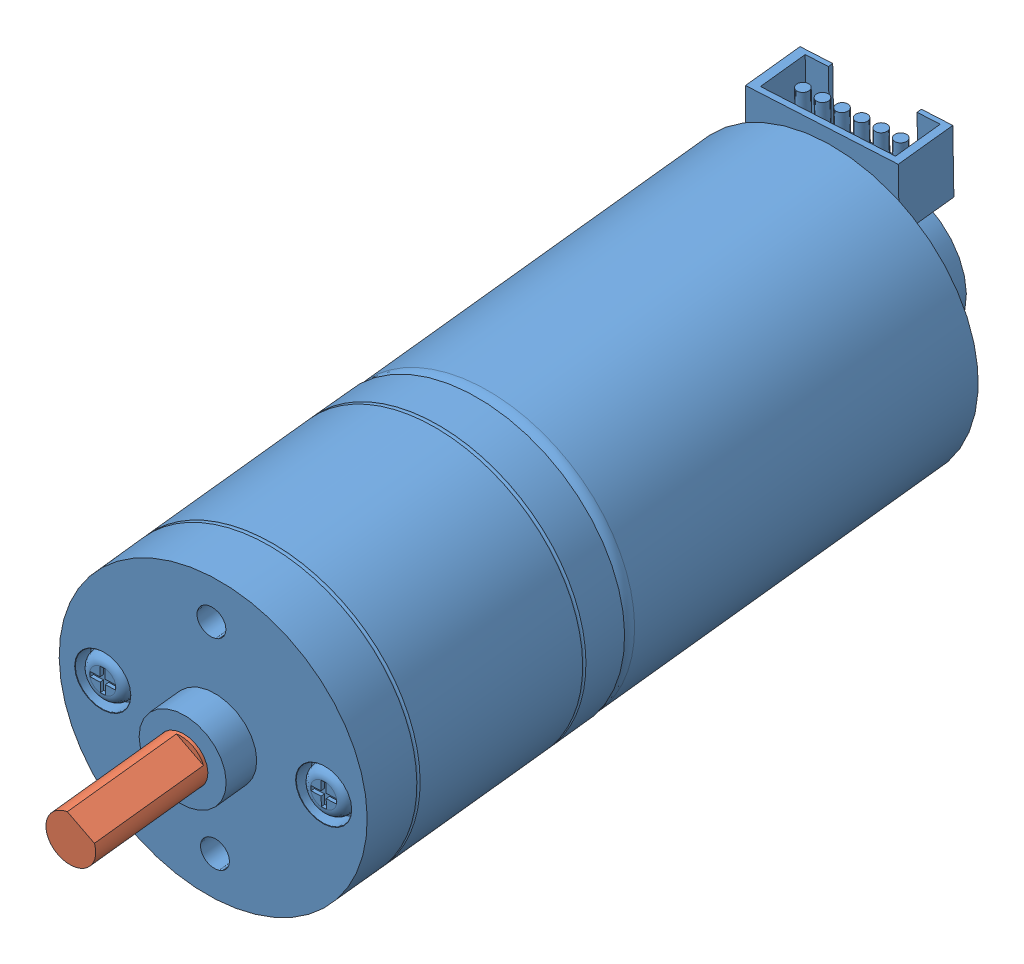
SolidWorks assembly 6V Motor Spin, configuration Default. Lengths in mm.
Overall size (29.63 28.32 78.39).
2 component instances, 2 part files, 2 mates.
Components (placement in the parent):
- Motor no spinny boi-1: Motor no spinny boi [Default] at (39.6165 36.3483 7.7453) x (0.997226 -0.015871 -0.072721) z (0.072098 -0.036799 0.996718) size (24.4 25.49 66.9)
- Motor spinny boi-1: Motor spinny boi [Default] at (39.6165 36.3483 7.7453) x (0.547957 0.836461 -0.008754) z (0.072098 -0.036799 0.996718) size (3.95 3.95 13.05)
Mates (geometry in assembly coordinates):
- Coincident1: coincident: plane of Motor no spinny boi-1 through (43.5531 34.3391 62.1662) normal (0.072098 -0.036799 0.996718); plane of Motor spinny boi-1 through (43.5531 34.3391 62.1662) normal (-0.072098 0.036799 -0.996718)
- Concentric1: concentric: circle of Motor no spinny boi-1; circle of Motor spinny boi-1
